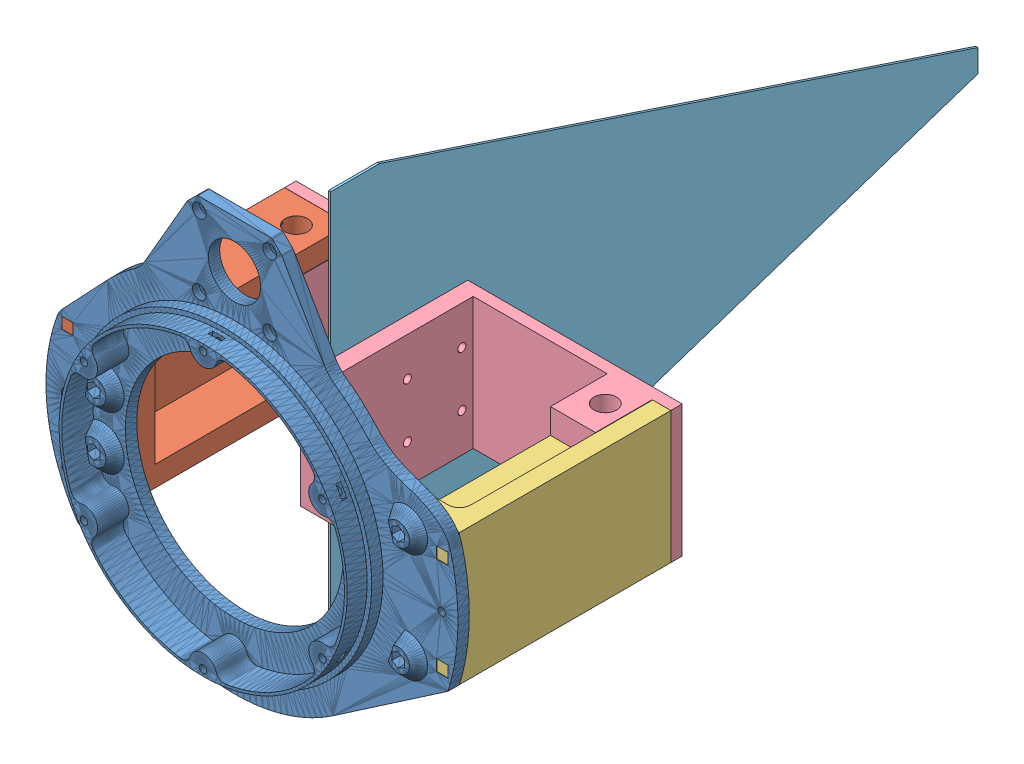
SolidWorks assembly Sunflower_logper_mount, configuration Default. Lengths in mm.
Overall size (181.35 197.43 341.88).
5 component instances, 5 part files, 0 mates.
Components (placement in the parent):
- Pan_Mount_Sunflower_logper-1: Pan_Mount_Sunflower_logper [Default] at (59.0671 99.4425 141.3302) size (181.35 181.99 18.8)
- Gear_Side_Support_sunflower_logper-1: Gear_Side_Support_sunflower_logper [Default] at (-16.9209 120.1353 133.2887) x (0 -1 0) z (1 0 0) size (58 98 28)
- Idle_Side_Support_wallmount_sunflower_logper-1: Idle_Side_Support_wallmount_sunflower_logper [Default] at (153.0824 99.4817 133.241) x (0 1 0) z (-1 0 0) size (58 98 28)
- logper_wallmount_holder-1: logper_wallmount_holder [Default] at (68.0819 99.4826 43.2299) size (170 58 65)
- Logper_model-1: Logper_model [Default] at (58.3412 99.5165 -39.2495) x (0 0 -1) z (0 1 0) size (285 1 185)
